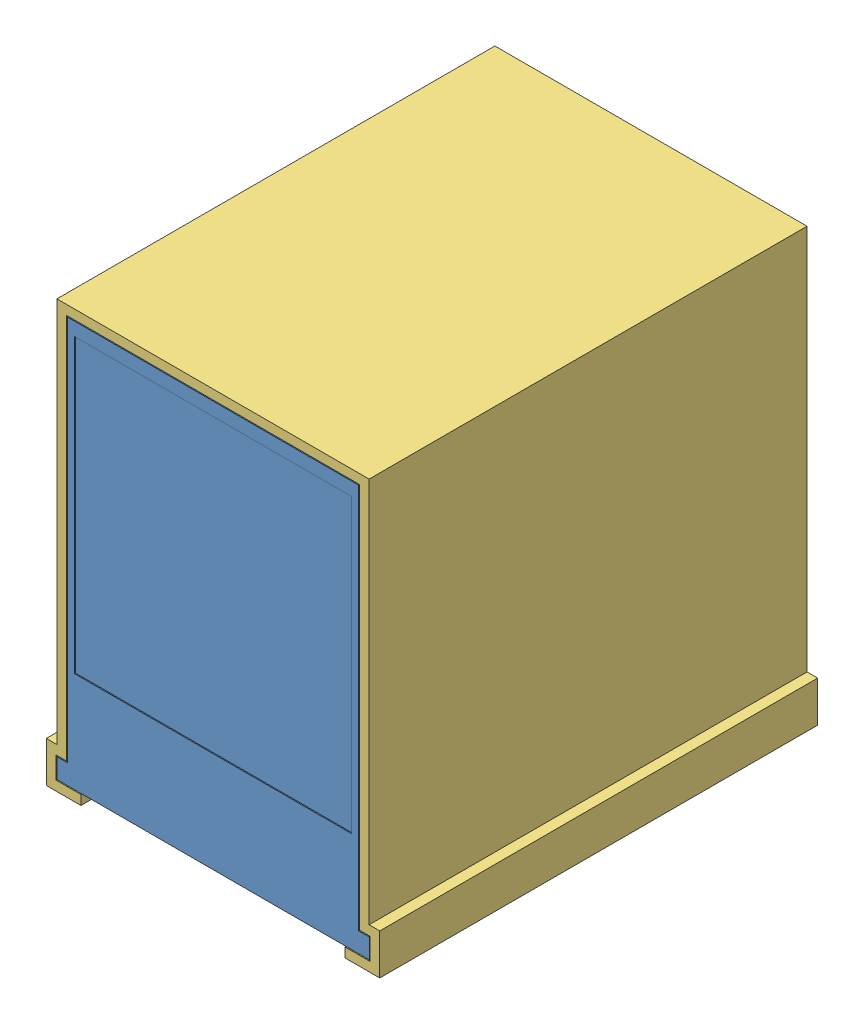
SolidWorks assembly Assem1, configuration Default. Lengths in mm.
Overall size (33.69 43.12 44.25).
3 component instances, 3 part files, 7 mates.
Components (placement in the parent):
- Screen-1: Screen [Default] at origin size (31.57 41 44.25)
- Led Panel-1: Led Panel [Default] at (0 19.95 -36.25) size (28.1 38.1 9.75)
- LED Panel Bracket v1-1: LED Panel Bracket v1 [Default] at origin size (33.69 43.12 44.25)
Mates (geometry in assembly coordinates):
- Coincident1: coincident aligned: plane of Screen-1 through (-14.71 39 -2.56) normal (0 1 0); plane of Led Panel-1 through (-14.05 39 -34.75) normal (0 1 0)
- Width1: width aligned: plane of Screen-1 through (-14.71 39 -2.56) normal (-1 0 0); plane of Screen-1 through (14.71 39 -2.56) normal (1 0 0); plane of Led Panel-1 through (-14.05 0.9 -34.75) normal (-1 0 0); plane of Led Panel-1 through (14.05 0.9 -34.75) normal (1 0 0)
- Distance1: distance = 8 mm aligned: plane of Led Panel-1 through (0 19.95 -36.25) normal (0 0 -1); plane of Screen-1 through (-15.785 -2 -44.25) normal (0 0 -1)
- InPlace1: in place: plane of ? through (-15.785 -2 0) normal (0 0 1); plane of ? through (0 0 0) normal (0 0 1); moOrthogonalPlaneRef_w of ? through (-15.785 -2 0) normal (0 0 1); plane of ? through (0 0 0) normal (0 1 0); plane of ? through (-15.785 -2 0) normal (0 0 1); plane of ? through (0 0 0) normal (1 0 0); plane of ? through (-15.785 -2 0) normal (0 0 1); unknown of ?
- Coincident2: coincident aligned: plane of Screen-1; plane of LED Panel Bracket v1-1
- Coincident3: coincident aligned: moOrthogonalPlaneRef_w of Screen-1 through (0 0 0) normal (0 1 0); plane of LED Panel Bracket v1-1 through (0 0 0) normal (0 1 0)
- Coincident4: coincident anti-aligned: moOrthogonalPlaneRef_w of Screen-1 through (0 0 0) normal (-1 0 0); plane of LED Panel Bracket v1-1 through (0 0 0) normal (1 0 0)
